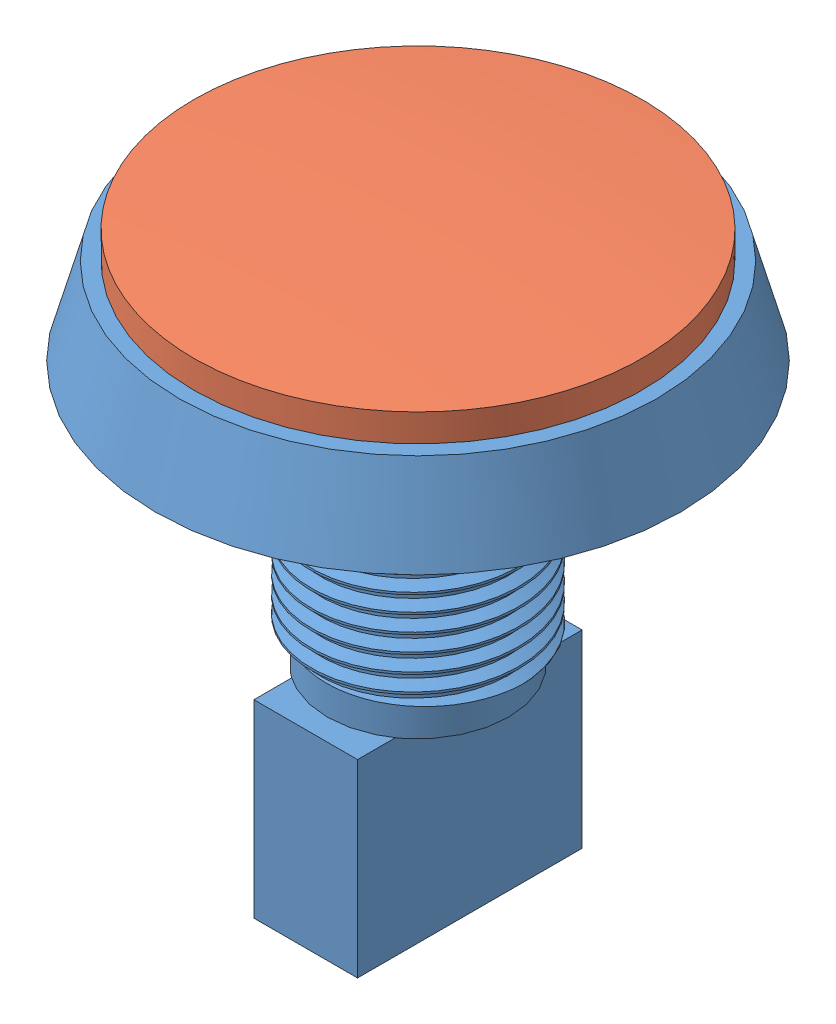
SolidWorks assembly arcade_button_60mm_white, configuration Default. Lengths in mm.
Overall size (60.8 66.8 60.8).
2 component instances, 2 part files, 2 mates.
Components (placement in the parent):
- arcade_button_60mm-1: arcade_button_60mm [Default] at origin size (60.8 62.4 60.8)
- arcade_button_60mm_white-1: arcade_button_60mm_white [Default] at (0 10 0) size (51.9 4.4 51.9)
Mates (geometry in assembly coordinates):
- Coincident11: coincident anti-aligned: plane of arcade_button_60mm-1 through (-27.65 10 0) normal (0 1 0); plane of arcade_button_60mm_white-1 through (0 10 0) normal (0 -1 0)
- Concentric11: concentric aligned: line of arcade_button_60mm-1 through (10 0 0) axis (0 0 1); line of arcade_button_60mm_white-1 through (4.4 0 10) axis (0 0 1)
